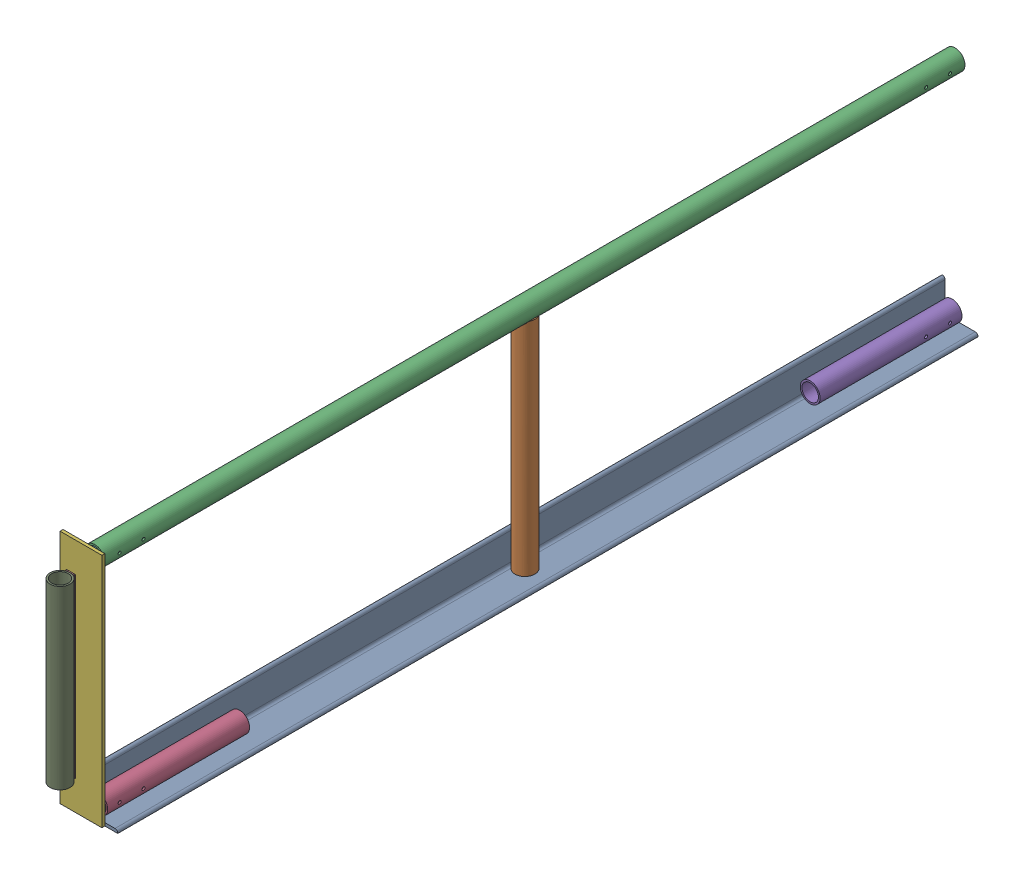
SolidWorks assembly FE-00024_ASM, configuration Default. Lengths in mm.
Overall size (109.89 508 1886.05).
12 component instances, 8 part files, 0 mates.
Components (placement in the parent):
- FE-00005_ASM-1: FE-00005_ASM [Default] at origin size (76.2 507.65 1828.8)
  - FE-00005-01-1: FE-00005-01 [Default] at origin size (76.2 76.2 1828.8)
  - FE-00005-03-1: FE-00005-03 [Default] at (27.432 6.35 914.4) size (42.16 471.23 42.16)
  - FE-00005-04-1: FE-00005-04 [Default] at (27.432 486.5688 0) size (42.16 42.16 1828.8)
  - FE-00005-02-1: FE-00005-02 [Default] at (27.432 27.432 1520.825) size (42.16 42.16 301.62)
  - FE-00005-02-2: FE-00005-02 [Default] at (27.432 27.432 307.975) x (1 0 0) z (0 0 -1) size (42.16 42.16 301.62)
- FE-00018_ASM-1: FE-00018_ASM [Default] at (-33.6868 6.35 1835.15) size (88.9 501.65 152.5)
  - FE-00018-03-1: FE-00018-03 [Default] at origin size (88.9 501.65 6.35)
  - FE-00018-02-1: FE-00018-02 [Default] at (61.1187 480.2188 -101.6) size (33.4 33.4 101.6)
  - FE-00018-02-2: FE-00018-02 [Default] at (61.1124 21.4312 -101.6) size (33.4 33.4 101.6)
  - FE-00018-01-1: FE-00018-01 [Default] at (23.368 63.5 29.8196) x (1 0 0) z (0 1 0) size (42.16 42.16 374.65)
  - FE-00018-04-1: FE-00018-04 [Default] at (23.368 250.825 6.35) size (19.05 374.65 2.38)
